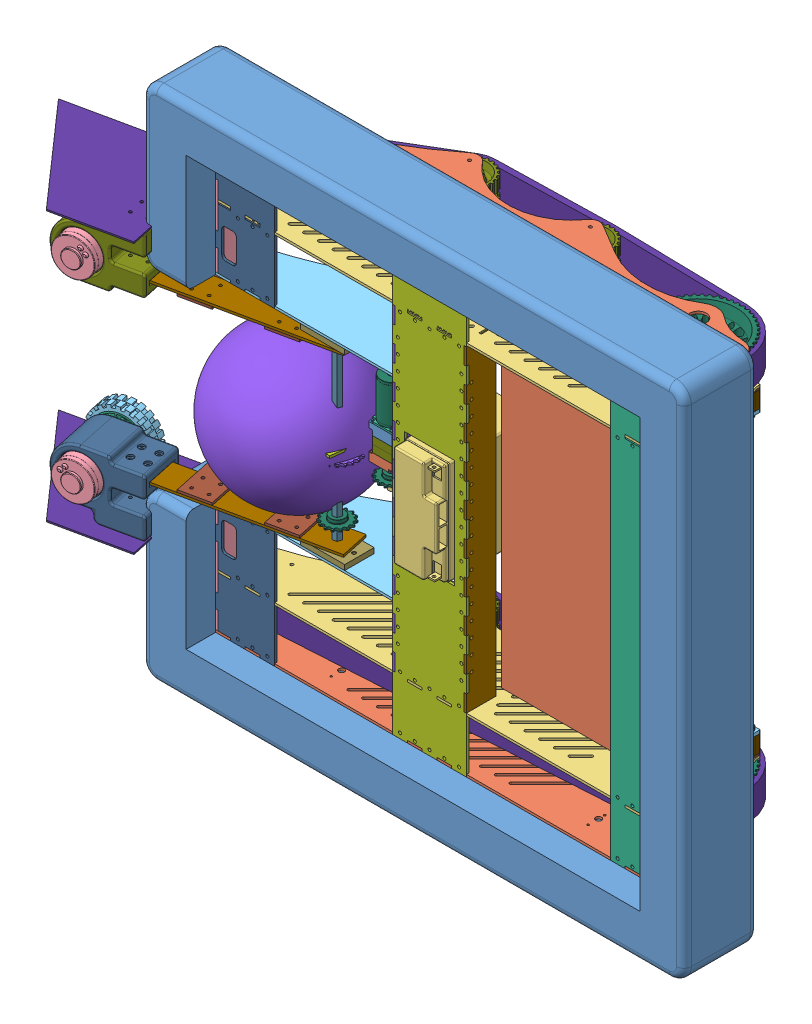
SolidWorks assembly 2016 Robot V2, configuration Default. Lengths in mm.
Overall size (1186.64 889 425.4).
244 component instances, 88 part files, 49 mates.
Components (placement in the parent):
- Rear-1: Rear [Default] at origin size (4.06 736.6 127)
- Side-1: Side [Default] at (-97.9 364.236 -84.1375) x (0 -1 0) z (0 0 1) size (4.06 781.05 206.38)
- Side-2: Side [Default] at (-97.9 -368.3 -84.1375) x (0 -1 0) z (0 0 1) size (4.06 781.05 206.38)
- Imported3-1: Imported3 [Default] at (-97.9 275.2905 -84.1375) x (0 -1 0) z (0 0 1) size (4.07 781.05 206.38)
- Imported3-2: Imported3 [Default] at (-97.9 -277.114 -84.1375) x (0 -1 0) z (0 0 1) size (4.07 781.05 206.38)
- Front-1: Front [Default] at (-781.05 266.7 25.4) size (4.06 203.2 76.2)
- Front-2: Front [Default] at (-776.986 -266.7 25.4) x (-1 0 0) z (0 0 1) size (4.06 203.2 76.2)
- Inside-1: Inside [Default] at (-97.9 165.1 -84.1375) x (0 -1 0) z (0 0 1) size (4.06 308.86 152.4)
- Inside-2: Inside [Default] at (-97.9 -169.164 -84.1375) x (0 -1 0) z (0 0 1) size (4.06 308.86 152.4)
- RearTop-1: RearTop [Default] at (-50.8 0 59.436) x (0 0 -1) z (1 0 0) size (4.06 736.6 101.6)
- Center-1: Center [Default] at (-412.75 0 63.5) x (0 0 1) z (-1 0 0) size (4.06 736.6 127)
- Imported8-1: Imported8 [Default] at (-476.25 0 25.4) size (4.06 554.23 76.2)
- Imported9-1: Imported9 [Default] at (-353.314 0 25.4) size (4.06 554.23 50.8)
- FrontTop-1: FrontTop [Default] at (-730.25 266.7 59.436) x (0 0 1) z (-1 0 0) size (4.06 203.2 101.6)
- FrontTop-2: FrontTop [Default] at (-730.25 -266.7 63.5) x (0 0 -1) z (-1 0 0) size (4.06 203.2 101.6)
- Imported11-1: Imported11 [Default] at (-63.0846 163.0378 -87.64) x (-1 0 0.000624) z (0 1 0) size (146.08 127 198.84)
  - Imported11-1: Imported11 [Default] at (-3.3906 30.1762 78.8009) size (17.53 17.53 1.47)
  - Imported12-1: Imported12 [Default] at (73.0258 30.1762 94.4473) x (0 0 1) z (-1 0 0) size (1.12 14.83 14.83)
  - Imported13-1: Imported13 [Default] at (33.4941 11.4893 125.5831) x (0 0 1) z (-0.997664 0.068316 0) size (17.78 3.17 3.18)
  - Imported14-1: Imported14 [Default] at (-20.7449 79.3887 68.1837) x (1 0 0) z (0 1 0) size (9.53 57.35 9.53)
  - Imported15-1: Imported15 [Default] at (40.6889 53.1471 81.8489) x (0.923728 0.383049 0) z (0 0 -1) size (24.69 24.69 7.16)
  - Imported15-2: Imported15 [Default] at (43.7045 38.1296 107.5537) size (24.69 24.69 7.16)
  - Imported16-1: Imported16 [Default] at (90.4055 79.3887 112.2527) x (1 0 0) z (0 -1 0) size (11.11 8.13 12.83)
  - Imported11-2: Imported11 [Default] at (-3.3906 30.1762 80.2741) size (17.53 17.53 1.47)
  - Imported17-1: Imported17 [Default] at (62.138 11.0174 96.4031) x (1 0 0) z (0 1 0) size (19.07 1.27 20.95)
  - Imported18-1: Imported18 [Default] at (-20.7449 79.3887 80.3249) size (127 14.35 28.75)
  - Imported14-2: Imported14 [Default] at (-20.7449 -31.7363 68.1837) x (1 0 0) z (0 1 0) size (9.53 57.35 9.53)
  - Imported19-1: Imported19 [Default] at (-3.3906 4.7762 85.1509) x (0 0 -1) z (1 0 0) size (17.53 7.94 7.94)
  - Imported20-1: Imported20 [Default] at (43.7045 -2.5612 107.5029) size (31.75 31.75 7.95)
  - Imported21-1: Imported21 [Default] at (34.8176 3.4808 154.3659) x (0 0 -1) z (1 0 0) size (1.4 15.88 15.88)
  - Imported11-3: Imported11 [Default] at (73.0258 30.1762 78.8009) size (17.53 17.53 1.47)
  - Imported22-1: Imported22 [Default] at (34.8176 44.1716 92.0089) x (0 0 -1) z (1 0 0) size (10.16 65.97 66.04)
  - Imported23-1: Imported23 [Default] at (21.1445 38.6364 74.7369) x (1 0 0) z (0 1 0) size (127 5.59 127)
  - Imported14-3: Imported14 [Default] at (90.3801 -31.7363 68.1837) x (1 0 0) z (0 1 0) size (9.53 57.35 9.53)
  - Imported19-2: Imported19 [Default] at (-3.3906 55.5762 85.1509) x (0 0 -1) z (1 0 0) size (17.53 7.94 7.94)
  - Imported24-1: Imported24 [Default] at (-3.3906 30.1762 81.7473) size (20.03 20.32 12.7)
  - Imported25-1: Imported25 [Default] at (34.8176 3.4808 159.8269) x (0.554675 -0.832067 0) z (-0.832067 -0.554675 0) size (11.69 16.79 11.69)
  - Imported11-4: Imported11 [Default] at (73.0258 30.1762 80.2741) size (17.53 17.53 1.47)
  - Imported26-1: Imported26 [Default] at (34.843 44.1716 92.0089) x (0 0 1) z (-1 0 0) size (15.14 19.97 20.32)
  - Imported18-2: Imported18 [Default] at (90.4055 -31.7363 80.3249) x (-1 0 0) z (0 0 1) size (127 14.35 28.75)
  - Imported16-2: Imported16 [Default] at (-20.7195 79.3887 112.2527) x (1 0 0) z (0 -1 0) size (11.11 8.13 12.83)
  - Imported19-3: Imported19 [Default] at (73.0258 55.5762 85.1509) x (0 0 -1) z (1 0 0) size (17.53 7.94 7.94)
  - Imported24-2: Imported24 [Default] at (73.0258 30.1762 81.7473) x (0.98536 0.170489 0) z (0 0 1) size (20.03 20.32 12.7)
  - Imported27-1: Imported27 [Default] at (-25.2074 30.9762 84.4473) x (0 0 1) z (0 -1 0) size (10.51 2 2.25)
  - Imported28-1: Imported28 [Default] at (34.8176 3.4808 96.4031) x (0.997664 -0.068316 0) z (0 0 1) size (65.97 66.04 10.62)
  - Imported29-1: Imported29 [Default] at (21.1699 38.6364 109.0777) x (1 0 0) z (0 1 0) size (127 3.17 127)
  - Imported30-1: Imported30 [Default] at (34.8176 44.1716 75.8037) x (0.5 -0.866025 0) z (0 0 1) size (11 9.53 38.11)
  - Imported16-3: Imported16 [Default] at (-20.7195 -31.7363 112.2527) x (1 0 0) z (0 -1 0) size (11.11 8.13 12.83)
  - Imported19-4: Imported19 [Default] at (73.0258 4.7762 85.1509) x (0 0 -1) z (1 0 0) size (17.53 7.94 7.94)
  - Imported12-2: Imported12 [Default] at (-3.3906 30.1762 94.4473) x (0 0 1) z (-1 0 0) size (1.12 14.83 14.83)
  - Imported27-2: Imported27 [Default] at (79.0195 13.1317 84.4473) x (0 0 1) z (0.98536 0.170489 0) size (10.51 2 2.25)
  - Imported14-4: Imported14 [Default] at (90.3801 79.3887 68.1837) x (1 0 0) z (0 1 0) size (9.53 57.35 9.53)
  - Imported15-3: Imported15 [Default] at (40.6889 12.4563 81.8489) x (0.923728 0.383049 0) z (0 0 -1) size (24.69 24.69 7.16)
  - Imported31-1: Imported31 [Default] at (-2.2613 22.7278 107.2489) x (-0.997664 0.068316 0) z (0.068316 0.997664 0) size (14.66 92.33 12.7)
  - Imported16-4: Imported16 [Default] at (90.4055 -31.7363 112.2527) x (1 0 0) z (0 -1 0) size (11.11 8.13 12.83)
  - Imported32-1: Imported32 [Default] at (-3.3906 30.1762 67.7369) x (1 0 0) z (0 -1 0) size (69.66 149.34 65.98)
  - Imported32-2: Imported32 [Default] at (73.0258 30.1762 67.7369) x (1 0 0) z (0 -1 0) size (69.66 149.34 65.98)
- Imported11-2: Imported11 [Default] at (-132.7154 -160.7973 -87.64) x (1 0 0.000624) z (0 -1 0) size (146.08 127 198.84)
  - Imported11-1: Imported11 [Default] at (-3.3906 30.1762 78.8009) size (17.53 17.53 1.47)
  - Imported12-1: Imported12 [Default] at (73.0258 30.1762 94.4473) x (0 0 1) z (-1 0 0) size (1.12 14.83 14.83)
  - Imported13-1: Imported13 [Default] at (33.4941 11.4893 125.5831) x (0 0 1) z (-0.997664 0.068316 0) size (17.78 3.17 3.18)
  - Imported14-1: Imported14 [Default] at (-20.7449 79.3887 68.1837) x (1 0 0) z (0 1 0) size (9.53 57.35 9.53)
  - Imported15-1: Imported15 [Default] at (40.6889 53.1471 81.8489) x (0.923728 0.383049 0) z (0 0 -1) size (24.69 24.69 7.16)
  - Imported15-2: Imported15 [Default] at (43.7045 38.1296 107.5537) size (24.69 24.69 7.16)
  - Imported16-1: Imported16 [Default] at (90.4055 79.3887 112.2527) x (1 0 0) z (0 -1 0) size (11.11 8.13 12.83)
  - Imported11-2: Imported11 [Default] at (-3.3906 30.1762 80.2741) size (17.53 17.53 1.47)
  - Imported17-1: Imported17 [Default] at (62.138 11.0174 96.4031) x (1 0 0) z (0 1 0) size (19.07 1.27 20.95)
  - Imported18-1: Imported18 [Default] at (-20.7449 79.3887 80.3249) size (127 14.35 28.75)
  - Imported14-2: Imported14 [Default] at (-20.7449 -31.7363 68.1837) x (1 0 0) z (0 1 0) size (9.53 57.35 9.53)
  - Imported19-1: Imported19 [Default] at (-3.3906 4.7762 85.1509) x (0 0 -1) z (1 0 0) size (17.53 7.94 7.94)
  - Imported20-1: Imported20 [Default] at (43.7045 -2.5612 107.5029) size (31.75 31.75 7.95)
  - Imported21-1: Imported21 [Default] at (34.8176 3.4808 154.3659) x (0 0 -1) z (1 0 0) size (1.4 15.88 15.88)
  - Imported11-3: Imported11 [Default] at (73.0258 30.1762 78.8009) size (17.53 17.53 1.47)
  - Imported22-1: Imported22 [Default] at (34.8176 44.1716 92.0089) x (0 0 -1) z (1 0 0) size (10.16 65.97 66.04)
  - Imported23-1: Imported23 [Default] at (21.1445 38.6364 74.7369) x (1 0 0) z (0 1 0) size (127 5.59 127)
  - Imported14-3: Imported14 [Default] at (90.3801 -31.7363 68.1837) x (1 0 0) z (0 1 0) size (9.53 57.35 9.53)
  - Imported19-2: Imported19 [Default] at (-3.3906 55.5762 85.1509) x (0 0 -1) z (1 0 0) size (17.53 7.94 7.94)
  - Imported24-1: Imported24 [Default] at (-3.3906 30.1762 81.7473) size (20.03 20.32 12.7)
  - Imported25-1: Imported25 [Default] at (34.8176 3.4808 159.8269) x (0.554675 -0.832067 0) z (-0.832067 -0.554675 0) size (11.69 16.79 11.69)
  - Imported11-4: Imported11 [Default] at (73.0258 30.1762 80.2741) size (17.53 17.53 1.47)
  - Imported26-1: Imported26 [Default] at (34.843 44.1716 92.0089) x (0 0 1) z (-1 0 0) size (15.14 19.97 20.32)
  - Imported18-2: Imported18 [Default] at (90.4055 -31.7363 80.3249) x (-1 0 0) z (0 0 1) size (127 14.35 28.75)
  - Imported16-2: Imported16 [Default] at (-20.7195 79.3887 112.2527) x (1 0 0) z (0 -1 0) size (11.11 8.13 12.83)
  - Imported19-3: Imported19 [Default] at (73.0258 55.5762 85.1509) x (0 0 -1) z (1 0 0) size (17.53 7.94 7.94)
  - Imported24-2: Imported24 [Default] at (73.0258 30.1762 81.7473) x (0.98536 0.170489 0) z (0 0 1) size (20.03 20.32 12.7)
  - Imported27-1: Imported27 [Default] at (-25.2074 30.9762 84.4473) x (0 0 1) z (0 -1 0) size (10.51 2 2.25)
  - Imported28-1: Imported28 [Default] at (34.8176 3.4808 96.4031) x (0.997664 -0.068316 0) z (0 0 1) size (65.97 66.04 10.62)
  - Imported29-1: Imported29 [Default] at (21.1699 38.6364 109.0777) x (1 0 0) z (0 1 0) size (127 3.17 127)
  - Imported30-1: Imported30 [Default] at (34.8176 44.1716 75.8037) x (0.5 -0.866025 0) z (0 0 1) size (11 9.53 38.11)
  - Imported16-3: Imported16 [Default] at (-20.7195 -31.7363 112.2527) x (1 0 0) z (0 -1 0) size (11.11 8.13 12.83)
  - Imported19-4: Imported19 [Default] at (73.0258 4.7762 85.1509) x (0 0 -1) z (1 0 0) size (17.53 7.94 7.94)
  - Imported12-2: Imported12 [Default] at (-3.3906 30.1762 94.4473) x (0 0 1) z (-1 0 0) size (1.12 14.83 14.83)
  - Imported27-2: Imported27 [Default] at (79.0195 13.1317 84.4473) x (0 0 1) z (0.98536 0.170489 0) size (10.51 2 2.25)
  - Imported14-4: Imported14 [Default] at (90.3801 79.3887 68.1837) x (1 0 0) z (0 1 0) size (9.53 57.35 9.53)
  - Imported15-3: Imported15 [Default] at (40.6889 12.4563 81.8489) x (0.923728 0.383049 0) z (0 0 -1) size (24.69 24.69 7.16)
  - Imported31-1: Imported31 [Default] at (-2.2613 22.7278 107.2489) x (-0.997664 0.068316 0) z (0.068316 0.997664 0) size (14.66 92.33 12.7)
  - Imported16-4: Imported16 [Default] at (90.4055 -31.7363 112.2527) x (1 0 0) z (0 -1 0) size (11.11 8.13 12.83)
  - Imported32-1: Imported32 [Default] at (-3.3906 30.1762 67.7369) x (1 0 0) z (0 -1 0) size (69.66 149.34 65.98)
  - Imported32-2: Imported32 [Default] at (73.0258 30.1762 67.7369) x (1 0 0) z (0 -1 0) size (69.66 149.34 65.98)
- Imported33-1: Imported33 [Default] at (-97.9 322.9073 -84.1375) x (1 0 0) z (0 -1 0) size (150.76 150.76 55)
- Imported33-2: Imported33 [Default] at (-97.9 -320.6832 -84.1375) x (1 0 0) z (0 -1 0) size (150.76 150.76 55)
- Imported34-1: Imported34 [Default] at (-326.5 322.9073 -127) x (1 0 0) z (0 -1 0) size (74.17 74.17 55)
- Imported34-2: Imported34 [Default] at (-529.7 322.9073 -122.2375) x (1 0 0) z (0 -1 0) size (74.17 74.17 55)
- Imported34-3: Imported34 [Default] at (-721.25 322.9073 -7.9375) x (1 0 0) z (0 -1 0) size (74.17 74.17 55)
- Imported34-4: Imported34 [Default] at (-326.5 -320.6832 -127) x (1 0 0) z (0 -1 0) size (74.17 74.17 55)
- Imported34-5: Imported34 [Default] at (-529.7 -320.6832 -122.2375) x (1 0 0) z (0 -1 0) size (74.17 74.17 55)
- Imported34-6: Imported34 [Default] at (-721.25 -320.6832 -7.9375) x (1 0 0) z (0 -1 0) size (74.17 74.17 55)
- Belt-1: Belt [Default] at (-97.9 -320.6832 -84.1375) x (0 -1 0) z (0 0 1) size (50 749.65 207.26)
- Belt-2: Belt [Default] at (-97.9 322.9073 -84.1375) x (0 -1 0) z (0 0 1) size (50 749.65 207.26)
- Imported36-1: Imported36 [Default] at (-46.609 -24.2798 -33.3802) x (0 0 -1) z (0 1 0) size (57.51 127.03 152.4)
- Bumpers-1: Bumpers [Default] at (58.7957 17.8751 -12.7) size (933.45 889 127.01)
- electrical pannel-1: electrical pannel [Default] at (-349.252 267.8202 -0.1479) x (0 -1 0) z (-1 0 0.000624) size (533.4 3.17 336.55)
- Robot Raido OM5P-AN-1: Robot Raido OM5P-AN [Default] at (-114.3 140.8202 2.8805) x (1 0 -0.000624) z (0 -1 0) size (69.89 25.47 95.8) (hidden)
- roboRIO-2: roboRIO [Default] at (-238.0682 170.8303 12.6097) x (1 0 -0.000624) z (0.000624 0 1) size (146.27 143.19 36.83) (hidden)
- Voltage Regulator Module-1: Voltage Regulator Module [Default] at (-282.4199 37.3519 10.0914) x (1 0 -0.000624) z (0 -1 0) size (56.39 27.88 51.56) (hidden)
- Power Distribution Panel-1: Power Distribution Panel [Default] at (-253.7472 -120.4748 9.6477) x (0 1 0) z (1 0 -0.000624) size (192.68 39.24 124.89) (hidden)
- Main Circuit Breaker 120A-1: Main Circuit Breaker 120A [Default] at (-53.594 -115.697 68.58) size (50.95 73.41 44.2) (hidden)
- Battery 12V-1: Battery 12V [Default] at (-388.6368 55.7869 -78.232) x (0 -1 0) z (0 0 1) size (177.8 76.2 167.13)
- Pneumatic Control Module-1: Pneumatic Control Module [Default] at (-200.9586 39.4117 7.3795) x (0 1 0) z (1 0 -0.000624) size (69.09 27.65 56.9) (hidden)
- talon-1: talon [Default] at (-88.9291 -231.3973 8.8344) x (0 1 0) z (1 0 -0.000624) size (30.21 20.94 104.68) (hidden)
- talon-2: talon [Default] at (-88.9291 -188.4847 8.8344) x (0 1 0) z (1 0 -0.000624) size (30.21 20.94 104.68) (hidden)
- talon-3: talon [Default] at (-88.9291 -102.6596 8.8344) x (0 1 0) z (1 0 -0.000624) size (30.21 20.94 104.68) (hidden)
- talon-4: talon [Default] at (-88.9291 -59.747 8.8344) x (0 1 0) z (1 0 -0.000624) size (30.21 20.94 104.68) (hidden)
- talon-5: talon [Default] at (-88.9291 -16.8344 8.8344) x (0 1 0) z (1 0 -0.000624) size (30.21 20.94 104.68) (hidden)
- talon-6: talon [Default] at (-88.9291 -145.5722 8.8344) x (0 1 0) z (1 0 -0.000624) size (30.21 20.94 104.68) (hidden)
- shooter v2-1: shooter v2 [Default] at (-476.25 165.1 -139.7) x (0 -1 0) z (-1 0 0) size (466.79 425.4 635.26) (flexible)
  - shooter boundry-1: shooter boundry [Default] at origin size (330.2 228.6 381) (hidden)
  - MiniCIM Motor-1: MiniCIM Motor [Default] at (-2.032 219.5677 468.844) x (0 0.978022 -0.208504) z (0 0.208504 0.978022) size (133.06 64.01 64.01)
  - 4 in HiGrip Wheel-1: 4 in HiGrip Wheel [Default] at (1.2293 197.6904 475.009) x (0 0.978022 -0.208504) z (-0.935788 0.073511 0.344815) size (35.12 101.6 101.6)
    - 4 in tread-1: 4 in tread [Default] at (-8.0517 2.5236 2.5343) size (25.4 101.6 101.6)
    - 4in 2013 Hub-1: 4in 2013 Hub [Default] at (-8.0517 2.5236 2.5343) size (35.12 82.55 82.55)
  - am-0320a_8mm_Key_Hub-1: am-0320a_8mm_Key_Hub [Default] at (-2.032 211.9293 470.4724) x (0.162565 -0.20573 -0.965012) z (0 -0.978022 0.208504) size (57.15 57.15 25.4)
  - am-0320a_8mm_Key_Hub-2: am-0320a_8mm_Key_Hub [Default] at (332.232 211.9293 470.4724) x (-0.795747 0.126276 0.592318) z (0 -0.978022 0.208504) size (57.15 57.15 25.4)
  - 4 in HiGrip Wheel-2: 4 in HiGrip Wheel [Default] at (330.8694 196.6949 470.3393) x (0 0.978022 -0.208504) z (0.922364 0.08055 0.377832) size (35.12 101.6 101.6)
    - 4 in tread-1: 4 in tread [Default] at (-8.0517 2.5236 2.5343) size (25.4 101.6 101.6)
    - 4in 2013 Hub-1: 4in 2013 Hub [Default] at (-8.0517 2.5236 2.5343) size (35.12 82.55 82.55)
  - MiniCIM Motor-2: MiniCIM Motor [Default] at (332.232 219.5677 468.844) x (0 0.978022 -0.208504) z (1 0 0) size (133.06 64.01 64.01)
  - ball-1: ball [Default] at (185.504 150.271 215.6704) x (0.724331 -0.676335 -0.133854) z (-0.671375 -0.64775 -0.360105) size (254 254 254)
  - shooter bar-1: shooter bar [Default] at (317.5 147.6623 101.1042) x (0 0.208504 0.978022) z (-1 0 0) size (330.2 50.8 4.06)
  - shooter bar-2: shooter bar [Default] at (16.764 147.6623 101.1042) x (0 0.208504 0.978022) z (-1 0 0) size (330.2 50.8 4.06)
  - CIM mount - right - 3d print-2: CIM mount - right - 3d print [Default] at (287.782 222.6252 513.6411) x (1 0 0) z (0 0.208504 0.978022) size (107.95 76.2 139.7)
  - shooter cross bar-3: shooter cross bar [Default] at (16.764 11.8517 194.9846) x (1 0 0) z (0 0.208504 0.978022) size (296.67 203.2 50.8)
  - shooter cross bar-4: shooter cross bar [Default] at (16.764 38.3317 319.1933) x (1 0 0) z (0 0.208504 0.978022) size (296.67 203.2 50.8)
  - bearing block-1: bearing block [Default] at (330.2 203.2 82.55) x (0 -1 0) z (-1 0 0) size (50.8 76.2 8.89)
  - bearing block-2: bearing block [Default] at (0 152.4 82.55) x (0 1 0) z (1 0 0) size (50.8 76.2 8.89)
  - .5in hex bearing-3: .5in hex bearing [Default] at (327.66 177.8 120.65) x (0 0.951243 0.308441) z (0 -0.308441 0.951243) size (31.72 7.92 31.72)
  - .5in hex bearing-4: .5in hex bearing [Default] at (2.54 177.8 120.65) x (0 -0.951243 -0.308441) z (0 -0.308441 0.951243) size (31.72 7.92 31.72)
  - shaft-2: shaft [Default] at (330.2 177.8 120.65) x (0 0.74274 -0.66958) z (-1 0 0) size (14.66 12.7 330.2)
  - s35-15he-500h-1: s35-15he-500h [Default] at (283.972 177.8 120.65) x (0 -0.208504 -0.978022) z (-1 0 0) size (50.14 50.4 10.29)
  - CIM mount - left - 3d print-1: CIM mount - left - 3d print [Default] at (42.418 222.6252 513.6411) x (1 0 0) z (0 0.208504 0.978022) size (107.95 76.2 139.7)
  - gate lifter-1: gate lifter [Default] at (395.732 144.4422 634.1921) x (0 -0.208504 -0.978022) z (1 0 0) size (241.3 203.2 2.54)
  - gate lifter-2: gate lifter [Default] at (-68.072 144.4422 634.1921) x (0 -0.208504 -0.978022) z (1 0 0) size (241.3 203.2 2.54)
  - bottom bar-1: bottom bar [Default] at (190.5 44.949 369.7242) x (0 -0.208504 -0.978022) z (1 0 0) size (177.8 4.06 50.8)
  - VEXpro-VersaPlanetary-2stage-with-BAG-1: VEXpro-VersaPlanetary-2stage-with-BAG [Default] at (215.175 106 33.7) x (0 0 1) z (-1 0 0) size (49.3 49.3 173.58)
    - 217-2625-001 Rev1-1: 217-2625-001 Rev1 [Default] at origin size (42 42 18)
    - 217-2625-002 Rev1-1: 217-2625-002 Rev1 [Default] at (0 0 -29.4) size (42 42 17.13)
    - 217-2625-003 Rev1-1: 217-2625-003 Rev1 [Default] at (0 0 -43.6478) x (0.966651 -0.256095 0) z (0 0 -1) size (17 17 64.12)
    - 217-2625-009 Rev1-1: 217-2625-009 Rev1 [Default] at (0 0 -3.48) x (-0.609619 0.792694 0) z (0 0 -1) size (18 18 13)
    - 217-2625-100-1: 217-2625-100 [Default] at (0 0 -18.8454) x (0.784104 -0.62063 0) z (0 0 1) size (39.26 38.9 12.7)
      - 217-2625-008 Rev1-1: 217-2625-008 Rev1 [Default] at origin size (34.7 34.7 4.7)
      - 217-2625-010 Rev1-1: 217-2625-010 Rev1 [Default] at (0 10.193 3.65) x (0.999813 0.019336 0) z (0 0 1) size (4 4 12)
      - 217-2625-010 Rev1-2: 217-2625-010 Rev1 [Default] at (8.691 -5.3258 3.65) size (4 4 12)
      - 217-2625-010 Rev1-3: 217-2625-010 Rev1 [Default] at (-8.691 -5.3258 3.65) size (4 4 12)
      - 217-2625-005 Rev1_Planet_Revolving_Follower01-1: 217-2625-005 Rev1_Planet_Revolving_Follower01 [Default] at (8.691 -5.3258 6.35) x (0.932816 0.360354 0) z (0 0 1) size (16.91 16.92 8)
      - 217-2625-005 Rev1_Planet_Revolving_Follower01-2: 217-2625-005 Rev1_Planet_Revolving_Follower01 [Default] at (-8.691 -5.3258 6.35) x (-0.932788 -0.360426 0) z (0 0 1) size (16.91 16.92 8)
      - 217-2625-005 Rev1_Planet_Revolving_Follower01-3: 217-2625-005 Rev1_Planet_Revolving_Follower01 [Default] at (0 10.193 6.35) x (0.893583 0.448898 0) z (0 0 1) size (16.91 16.92 8)
    - 217-2625-007 Rev1_Sun_Driver01-1: 217-2625-007 Rev1_Sun_Driver01 [Default] at (0 0 -11.5575) x (0.564419 -0.825488 0) z (0 0 1) size (14.49 14.49 12.72)
    - 217-2742-1: 217-2742 [Default] at (0 0 -51.4002) x (0 0 1) z (-0.997393 0.072165 0) size (7 28 28)
    - 217-2742-2: 217-2742 [Default] at (0 0 -43.1002) x (0 0 1) z (-1 0 0) size (7 28 28)
    - 217-2741-1: 217-2741 [Default] at (0 0 -7) x (0 0 1) z (-0.951311 0.308231 0) size (5 26 26)
    - TRUARC-MSH-15_98541A410-1: TRUARC-MSH-15_98541A410 [Default] at (0 0 -35.4954) x (0 0 -1) z (0.980859 -0.194721 0) size (1 19.6 17.4)
    - SPRGW0856-1102-012_9714K62-1: SPRGW0856-1102-012_9714K62 [Default] at (0 0 -44.1002) x (-0.695225 0.718792 0) z (-0.718792 -0.695225 0) size (29.09 5.11 30.79)
    - SSS1032-0125ZB_94105A824-1: SSS1032-0125ZB_94105A824 [Default] at (5.4759 4.2112 1.995) x (-0.605001 0.78669 -0.122849) z (0.792694 0.609619 0) size (4.83 4.84 3.3)
    - TRUARC-5103-68_97414A675_grv-1: TRUARC-5103-68_97414A675_grv [Default] at (1.1965 0.0349 -1.3834) x (0 0 -1) z (-0.029125 0.999576 0) size (1.07 15.49 20.19)
    - 217-3351-1: 217-3351 [Default] at (0 0 10.675) x (0 -1 0) z (0 0 -1) size (40.4 40.4 81.5)
    - 217-2816-001 Rev1-1: 217-2816-001 Rev1 [Default] at (0 0 -29.55) x (1 0 0) z (0 0 -1) size (42 42 14.5)
    - SSA_SSA0832-1750ZC-1: SSA_SSA0832-1750ZC [Default] at (-17.5 17.5 -47.261) x (-0.769034 -0.639207 0) z (0.639207 -0.769034 0) size (6.73 48.51 6.73)
    - SSA_SSA0832-1750ZC-2: SSA_SSA0832-1750ZC [Default] at (17.5 -17.5 -47.261) x (0.162252 0.986749 0) z (-0.986749 0.162252 0) size (6.73 48.51 6.73)
    - 217-2625-011 Rev1-1: 217-2625-011 Rev1 [Default] at (0 0 1.37) x (-0.792694 -0.609619 0) z (-0.609619 0.792694 0) size (8.01 7.5 7.94)
    - SSA_SSA0832-0500ZC-1: SSA_SSA0832-0500ZC [Default] at (-17.5 17.5 10.675) x (0.592766 0.805375 0) z (0.805375 -0.592766 0) size (6.73 16.76 6.73)
    - SSA_SSA0832-0500ZC-2: SSA_SSA0832-0500ZC [Default] at (17.5 -17.5 10.675) x (-0.592766 -0.805375 0) z (-0.805375 0.592766 0) size (6.73 16.76 6.73)
    - SSHCM004_SSHCM004070010C-1: SSHCM004_SSHCM004070010C [Default] at (0 -12.5 7.5) x (-0.451598 -0.892221 0) z (0.892221 -0.451598 0) size (7 14 7)
    - SSHCM004_SSHCM004070010C-2: SSHCM004_SSHCM004070010C [Default] at (0 12.5 7.5) x (-0.447517 -0.894275 0) z (0.894275 -0.447517 0) size (7 14 7)
    - 217-2816-001 Rev1-2: 217-2816-001 Rev1 [Default] at (0 0 -16.85) x (1 0 0) z (0 0 -1) size (42 42 14.5)
    - 217-2818 Rev1-1: 217-2818 Rev1 [Default] at (0 0 -31.5454) size (49.07 49.07 17.4)
      - 217-2725-001 Rev1_24t Sun-1: 217-2725-001 Rev1_24t Sun [Default] at (0 0 8.7) size (14.45 14.45 12.7)
      - 217-2725-002 Rev1_24t Planet-1: 217-2725-002 Rev1_24t Planet [Default] at (-12.089 0 6.35) x (-0.130526 0.991445 0) z (0 0 -1) size (13.17 13.15 8)
      - 217-2724-002 Rev1-1: 217-2724-002 Rev1 [Default] x (0.707107 -0.707107 0) z (0 0 -1) size (34.7 34.7 4.7)
      - 217-2625-010 Rev1-1: 217-2625-010 Rev1 [Default] at (-12.089 0 3.65) x (0.971612 -0.236582 0) z (0 0 1) size (4 4 12)
      - 217-2725-002 Rev1_24t Planet-2: 217-2725-002 Rev1_24t Planet [Default] at (0 -12.089 6.35) x (-0.991445 -0.130526 0) z (0 0 -1) size (13.17 13.15 8)
      - 217-2725-002 Rev1_24t Planet-3: 217-2725-002 Rev1_24t Planet [Default] at (12.089 0 6.35) x (0.130526 -0.991445 0) z (0 0 -1) size (13.17 13.15 8)
      - 217-2725-002 Rev1_24t Planet-4: 217-2725-002 Rev1_24t Planet [Default] at (0 12.089 6.35) x (0.991445 0.130526 0) z (0 0 -1) size (13.17 13.15 8)
      - 217-2625-010 Rev1-2: 217-2625-010 Rev1 [Default] at (0 -12.089 3.65) x (0.236582 0.971612 0) z (0 0 1) size (4 4 12)
      - 217-2625-010 Rev1-3: 217-2625-010 Rev1 [Default] at (12.089 0 3.65) x (-0.971612 0.236582 0) z (0 0 1) size (4 4 12)
      - 217-2625-010 Rev1-4: 217-2625-010 Rev1 [Default] at (0 12.089 3.65) x (-0.236582 -0.971612 0) z (0 0 1) size (4 4 12)
    - 217-2822-003 Rev4-1: 217-2822-003 Rev4 [Default] at (0 0 9) x (0 -1 0) z (0 0 1) size (42 42 4.8)
  - s35-15he-500h-2: s35-15he-500h [Default] at (283.972 106 33.7) x (0 0.528305 -0.849055) z (-1 0 0) size (50.14 50.4 10.29)
  - .5in hex bearing-5: .5in hex bearing [Default] at (169.418 177.8 120.65) x (0 -0.208504 -0.978022) z (0 0.978022 -0.208504) size (31.72 7.92 31.72)
  - kicker-1: kicker [Default] at (163.068 29.7099 127.3655) x (0 0.126534 -0.991962) z (1 0 0) size (50.8 177.8 4.06)
  - VEXpro-VersaPlanetary-2stage-with-BAG-2: VEXpro-VersaPlanetary-2stage-with-BAG [Default] at (107.225 169.5 33.7) x (0 0 1) z (-1 0 0) size (49.3 49.3 173.58)
    - 217-2625-001 Rev1-1: 217-2625-001 Rev1 [Default] at origin size (42 42 18)
    - 217-2625-002 Rev1-1: 217-2625-002 Rev1 [Default] at (0 0 -29.4) size (42 42 17.13)
    - 217-2625-003 Rev1-1: 217-2625-003 Rev1 [Default] at (0 0 -43.6478) x (0.966651 -0.256095 0) z (0 0 -1) size (17 17 64.12)
    - 217-2625-009 Rev1-1: 217-2625-009 Rev1 [Default] at (0 0 -3.48) x (-0.609619 0.792694 0) z (0 0 -1) size (18 18 13)
    - 217-2625-100-1: 217-2625-100 [Default] at (0 0 -18.8454) x (0.784104 -0.62063 0) z (0 0 1) size (39.26 38.9 12.7)
      - 217-2625-008 Rev1-1: 217-2625-008 Rev1 [Default] at origin size (34.7 34.7 4.7)
      - 217-2625-010 Rev1-1: 217-2625-010 Rev1 [Default] at (0 10.193 3.65) x (0.999813 0.019336 0) z (0 0 1) size (4 4 12)
      - 217-2625-010 Rev1-2: 217-2625-010 Rev1 [Default] at (8.691 -5.3258 3.65) size (4 4 12)
      - 217-2625-010 Rev1-3: 217-2625-010 Rev1 [Default] at (-8.691 -5.3258 3.65) size (4 4 12)
      - 217-2625-005 Rev1_Planet_Revolving_Follower01-1: 217-2625-005 Rev1_Planet_Revolving_Follower01 [Default] at (8.691 -5.3258 6.35) x (0.932816 0.360354 0) z (0 0 1) size (16.91 16.92 8)
      - 217-2625-005 Rev1_Planet_Revolving_Follower01-2: 217-2625-005 Rev1_Planet_Revolving_Follower01 [Default] at (-8.691 -5.3258 6.35) x (-0.932788 -0.360426 0) z (0 0 1) size (16.91 16.92 8)
      - 217-2625-005 Rev1_Planet_Revolving_Follower01-3: 217-2625-005 Rev1_Planet_Revolving_Follower01 [Default] at (0 10.193 6.35) x (0.893583 0.448898 0) z (0 0 1) size (16.91 16.92 8)
    - 217-2625-007 Rev1_Sun_Driver01-1: 217-2625-007 Rev1_Sun_Driver01 [Default] at (0 0 -11.5575) x (0.564419 -0.825488 0) z (0 0 1) size (14.49 14.49 12.72)
    - 217-2742-1: 217-2742 [Default] at (0 0 -51.4002) x (0 0 1) z (-0.997393 0.072165 0) size (7 28 28)
    - 217-2742-2: 217-2742 [Default] at (0 0 -43.1002) x (0 0 1) z (-1 0 0) size (7 28 28)
    - 217-2741-1: 217-2741 [Default] at (0 0 -7) x (0 0 1) z (-0.951311 0.308231 0) size (5 26 26)
    - TRUARC-MSH-15_98541A410-1: TRUARC-MSH-15_98541A410 [Default] at (0 0 -35.4954) x (0 0 -1) z (0.980859 -0.194721 0) size (1 19.6 17.4)
    - SPRGW0856-1102-012_9714K62-1: SPRGW0856-1102-012_9714K62 [Default] at (0 0 -44.1002) x (-0.695225 0.718792 0) z (-0.718792 -0.695225 0) size (29.09 5.11 30.79)
    - SSS1032-0125ZB_94105A824-1: SSS1032-0125ZB_94105A824 [Default] at (5.4759 4.2112 1.995) x (-0.605001 0.78669 -0.122849) z (0.792694 0.609619 0) size (4.83 4.84 3.3)
    - TRUARC-5103-68_97414A675_grv-1: TRUARC-5103-68_97414A675_grv [Default] at (1.1965 0.0349 -1.3834) x (0 0 -1) z (-0.029125 0.999576 0) size (1.07 15.49 20.19)
    - 217-3351-1: 217-3351 [Default] at (0 0 10.675) x (0 -1 0) z (0 0 -1) size (40.4 40.4 81.5)
    - 217-2816-001 Rev1-1: 217-2816-001 Rev1 [Default] at (0 0 -29.55) x (1 0 0) z (0 0 -1) size (42 42 14.5)
    - SSA_SSA0832-1750ZC-1: SSA_SSA0832-1750ZC [Default] at (-17.5 17.5 -47.261) x (-0.769034 -0.639207 0) z (0.639207 -0.769034 0) size (6.73 48.51 6.73)
    - SSA_SSA0832-1750ZC-2: SSA_SSA0832-1750ZC [Default] at (17.5 -17.5 -47.261) x (0.162252 0.986749 0) z (-0.986749 0.162252 0) size (6.73 48.51 6.73)
    - 217-2625-011 Rev1-1: 217-2625-011 Rev1 [Default] at (0 0 1.37) x (-0.792694 -0.609619 0) z (-0.609619 0.792694 0) size (8.01 7.5 7.94)
    - SSA_SSA0832-0500ZC-1: SSA_SSA0832-0500ZC [Default] at (-17.5 17.5 10.675) x (0.592766 0.805375 0) z (0.805375 -0.592766 0) size (6.73 16.76 6.73)
    - SSA_SSA0832-0500ZC-2: SSA_SSA0832-0500ZC [Default] at (17.5 -17.5 10.675) x (-0.592766 -0.805375 0) z (-0.805375 0.592766 0) size (6.73 16.76 6.73)
    - SSHCM004_SSHCM004070010C-1: SSHCM004_SSHCM004070010C [Default] at (0 -12.5 7.5) x (-0.451598 -0.892221 0) z (0.892221 -0.451598 0) size (7 14 7)
    - SSHCM004_SSHCM004070010C-2: SSHCM004_SSHCM004070010C [Default] at (0 12.5 7.5) x (-0.447517 -0.894275 0) z (0.894275 -0.447517 0) size (7 14 7)
    - 217-2816-001 Rev1-2: 217-2816-001 Rev1 [Default] at (0 0 -16.85) x (1 0 0) z (0 0 -1) size (42 42 14.5)
    - 217-2818 Rev1-1: 217-2818 Rev1 [Default] at (0 0 -31.5454) size (49.07 49.07 17.4)
      - 217-2725-001 Rev1_24t Sun-1: 217-2725-001 Rev1_24t Sun [Default] at (0 0 8.7) size (14.45 14.45 12.7)
      - 217-2725-002 Rev1_24t Planet-1: 217-2725-002 Rev1_24t Planet [Default] at (-12.089 0 6.35) x (-0.130526 0.991445 0) z (0 0 -1) size (13.17 13.15 8)
      - 217-2724-002 Rev1-1: 217-2724-002 Rev1 [Default] x (0.707107 -0.707107 0) z (0 0 -1) size (34.7 34.7 4.7)
      - 217-2625-010 Rev1-1: 217-2625-010 Rev1 [Default] at (-12.089 0 3.65) x (0.971612 -0.236582 0) z (0 0 1) size (4 4 12)
      - 217-2725-002 Rev1_24t Planet-2: 217-2725-002 Rev1_24t Planet [Default] at (0 -12.089 6.35) x (-0.991445 -0.130526 0) z (0 0 -1) size (13.17 13.15 8)
      - 217-2725-002 Rev1_24t Planet-3: 217-2725-002 Rev1_24t Planet [Default] at (12.089 0 6.35) x (0.130526 -0.991445 0) z (0 0 -1) size (13.17 13.15 8)
      - 217-2725-002 Rev1_24t Planet-4: 217-2725-002 Rev1_24t Planet [Default] at (0 12.089 6.35) x (0.991445 0.130526 0) z (0 0 -1) size (13.17 13.15 8)
      - 217-2625-010 Rev1-2: 217-2625-010 Rev1 [Default] at (0 -12.089 3.65) x (0.236582 0.971612 0) z (0 0 1) size (4 4 12)
      - 217-2625-010 Rev1-3: 217-2625-010 Rev1 [Default] at (12.089 0 3.65) x (-0.971612 0.236582 0) z (0 0 1) size (4 4 12)
      - 217-2625-010 Rev1-4: 217-2625-010 Rev1 [Default] at (0 12.089 3.65) x (-0.236582 -0.971612 0) z (0 0 1) size (4 4 12)
    - 217-2822-003 Rev4-1: 217-2822-003 Rev4 [Default] at (0 0 9) x (0 -1 0) z (0 0 1) size (42 42 4.8)
  - s35-15he-500h-3: s35-15he-500h [Default] at (179.832 169.5 33.7) x (0 0.321712 -0.946838) z (-1 0 0) size (50.14 50.4 10.29)
  - am-0737-1: am-0737 [Default] at (181.864 177.8 120.65) x (0 0.795797 0.605563) z (-1 0 0) size (71.96 71.42 4.06)
Mates (geometry in assembly coordinates):
- Coincident1: coincident aligned: plane of Rear-1 through (-4.064 0 0) normal (-1 0 0); circle of Imported36-1
- Width1: width aligned: plane of Imported3-2 through (-97.9 -273.05 -84.1375) normal (0 1 0); plane of Imported3-1 through (-97.9 275.2905 -84.1375) normal (0 -1 0); plane of Imported36-1 through (-46.609 63.9852 -33.3802) normal (0 1 0); plane of Imported36-1 through (-46.609 -61.7448 -33.3802) normal (0 -1 0)
- Coincident3: coincident anti-aligned: plane of Imported11-1/Imported18-1 through (-42.2852 243.3627 -0.3395) normal (0.000624 0 1); plane of electrical pannel-1 through (-349.252 267.8202 -0.1479) normal (-0.000624 0 -1)
- Coincident15: coincident aligned: plane of electrical pannel-1 through (-349.25 267.8202 3.0271) normal (0.000624 0 1); plane of roboRIO-2 through (-311.5862 98.8637 3.0036) normal (0.000624 0 1)
- Distance3: distance = 25.4 mm: plane of roboRIO-2 through (-169.9988 242.4202 5.1474) normal (0 -1 0); line of electrical pannel-1 through (-12.7001 267.8202 2.817) axis (-1 0 0.000624)
- Coincident18: coincident anti-aligned: plane of electrical pannel-1 through (-349.25 267.8202 3.0271) normal (0.000624 0 1); plane of Voltage Regulator Module-1 through (-259.08 56.8992 2.9708) normal (-0.000624 0 -1)
- Distance7: distance = 38.1 mm: line of roboRIO-2 through (-303.5285 99.2404 5.3898) axis (1 0 -0.000624); line of Voltage Regulator Module-1 through (-259.08 61.2172 2.9454) axis (-1 0 0.000624)
- Width3: width anti-aligned: plane of Imported3-2 through (-97.9 -273.05 -84.1375) normal (0 1 0); plane of Imported3-1 through (-97.9 275.2905 -84.1375) normal (0 -1 0); plane of electrical pannel-1 through (-349.25 -265.5798 3.0271) normal (0 -1 0); plane of electrical pannel-1 through (-349.25 267.8202 3.0271) normal (0 1 0)
- Coincident25: coincident anti-aligned: plane of electrical pannel-1 through (-349.25 267.8202 3.0271) normal (0.000624 0 1); plane of Power Distribution Panel-1 through (-196.3474 -28.4506 2.9317) normal (-0.000624 0 -1)
- Coincident32: coincident: plane of Imported9-1 through (-349.25 0 25.4) normal (1 0 0); line of electrical pannel-1 through (-349.25 267.8202 3.0271) axis (0 -1 0)
- Distance11: distance = 38.1 mm: line of Voltage Regulator Module-1 through (-311.15 56.8992 2.9779) axis (0 -1 0); plane of electrical pannel-1 through (-349.25 267.8202 3.0271) normal (-1 0 0.000624)
- Distance13: distance = 38.1 mm: line of roboRIO-2 through (-311.1485 234.8002 5.3945) axis (0 -1 0); plane of electrical pannel-1 through (-349.25 267.8202 3.0271) normal (-1 0 0.000624)
- Width5: width anti-aligned: plane of Center-1 through (-369.8875 0 63.5) normal (-1 0 0); plane of Center-1 through (-455.6125 0 63.5) normal (1 0 0); plane of Battery 12V-1 through (-374.65 88.9 -78.232) normal (1 0 0); plane of Battery 12V-1 through (-450.85 88.9 -78.232) normal (-1 0 0)
- Width6: width aligned: plane of Center-1 through (-412.75 -93.6625 63.5) normal (0 1 0); plane of Center-1 through (-412.75 93.6625 63.5) normal (0 -1 0); plane of Battery 12V-1 through (-374.65 88.9 67.818) normal (0 1 0); plane of Battery 12V-1 through (-374.65 -88.9 -78.232) normal (0 -1 0)
- Distance15: distance = 25.4 mm aligned: plane of Battery 12V-1 through (-449.3726 -87.4226 88.9) normal (0 0 1); plane of Center-1 through (-412.75 0 63.5) normal (0 0 1)
- Coincident40: coincident anti-aligned: plane of electrical pannel-1 through (-349.25 267.8202 3.0271) normal (0.000624 0 1); plane of Pneumatic Control Module-1 through (-225.2692 8.9825 2.9497) normal (-0.000624 0 -1)
- Coincident45: coincident anti-aligned: plane of electrical pannel-1 through (-349.25 267.8202 3.0271) normal (0.000624 0 1); plane of talon-1 through (-88.9328 -231.3973 2.8646) normal (-0.000624 0 -1)
- Coincident50: coincident anti-aligned: plane of electrical pannel-1 through (-349.25 267.8202 3.0271) normal (0.000624 0 1); plane of talon-2 through (-88.9328 -188.4847 2.8646) normal (-0.000624 0 -1)
- Coincident57: coincident anti-aligned: plane of electrical pannel-1 through (-349.25 267.8202 3.0271) normal (0.000624 0 1); plane of talon-3 through (-88.9328 -102.6596 2.8646) normal (-0.000624 0 -1)
- Coincident61: coincident anti-aligned: plane of electrical pannel-1 through (-349.25 267.8202 3.0271) normal (0.000624 0 1); plane of talon-4 through (-88.9328 -59.747 2.8646) normal (-0.000624 0 -1)
- Coincident65: coincident anti-aligned: plane of electrical pannel-1 through (-349.25 267.8202 3.0271) normal (0.000624 0 1); plane of talon-5 through (-88.9328 -16.8344 2.8646) normal (-0.000624 0 -1)
- Distance41: distance = 25.4 mm: line of Pneumatic Control Module-1 through (-229.3586 33.2141 2.9523) axis (0 1 0); plane of Voltage Regulator Module-1 through (-254.762 56.8992 2.9427) normal (0.999858 0 0.016828)
- Coincident82: coincident anti-aligned: plane of electrical pannel-1 through (-349.25 267.8202 3.0271) normal (0.000624 0 1); plane of talon-6 through (-88.9328 -145.5722 2.8646) normal (-0.000624 0 -1)
- Distance47: distance = 6.35 mm: point of Imported36-1; plane of electrical pannel-1 through (-349.252 267.8202 -0.1479) normal (-0.000624 0 -1)
- Distance55: distance = 19.05 mm: plane of talon-1 through (-57.183 -246.5304 2.6448) normal (0.000011 -0.999848 0.017452); line of electrical pannel-1 through (-349.25 -265.5798 3.0271) axis (1 0 -0.000624)
- Distance56: distance = 44.45 mm: plane of talon-1 through (-57.1782 -246.3973 10.2648) normal (0.999993 0 0.003739); line of electrical pannel-1 through (-12.7001 -265.5798 2.817) axis (0 1 0)
- Coincident105: coincident aligned: plane of talon-1 through (-57.1782 -246.3973 10.2648) normal (0.999906 0 -0.013714); plane of talon-2 through (-57.1782 -203.4847 10.2648) normal (0.999906 0 -0.013714)
- Coincident106: coincident aligned: plane of talon-2 through (-57.1782 -203.4847 10.2648) normal (0.999906 0 -0.013714); plane of talon-6 through (-57.1782 -160.5722 10.2648) normal (0.999906 0 -0.013714)
- Distance57: distance = 12.7 mm: line of talon-1 through (-58.7515 -216.291 4.1759) axis (-1 0 0.000624); line of talon-2 through (-119.1125 -203.591 4.2136) axis (1 0 -0.000624)
- Distance58: distance = 12.7 mm: line of talon-6 through (-119.1125 -160.6785 4.2136) axis (1 0 -0.000624); line of talon-2 through (-58.7515 -173.3785 4.1759) axis (-1 0 0.000624)
- Coincident110: coincident aligned: plane of talon-3 through (-57.1782 -117.6596 10.2648) normal (0.999906 0 -0.013714); plane of talon-1 through (-57.1782 -246.3973 10.2648) normal (0.999906 0 -0.013714)
- Distance59: distance = 12.7 mm: line of talon-6 through (-58.7515 -130.4659 4.1759) axis (-1 0 0.000624); line of talon-3 through (-119.1125 -117.7659 4.2136) axis (1 0 -0.000624)
- Coincident112: coincident aligned: plane of talon-1 through (-57.1782 -246.3973 10.2648) normal (0.999906 0 -0.013714); plane of talon-4 through (-57.1782 -74.747 10.2648) normal (0.999906 0 -0.013714)
- Distance60: distance = 12.7 mm: line of talon-3 through (-58.7515 -87.5533 4.1759) axis (-1 0 0.000624); line of talon-4 through (-119.1125 -74.8533 4.2136) axis (1 0 -0.000624)
- Coincident114: coincident aligned: plane of talon-4 through (-57.1782 -74.747 10.2648) normal (0.999906 0 -0.013714); plane of talon-5 through (-57.1782 -31.8344 10.2648) normal (0.999906 0 -0.013714)
- Distance61: distance = 12.7 mm: line of talon-5 through (-119.1125 -31.9407 4.2136) axis (1 0 -0.000624); line of talon-4 through (-58.7515 -44.6407 4.1759) axis (-1 0 0.000624)
- Parallel25: parallel aligned: line of electrical pannel-1 through (-349.25 267.8202 3.0271) axis (0 -1 0); line of Power Distribution Panel-1 through (-311.1507 -38.2341 3.2618) axis (0 -1 0)
- Distance81: distance = 38.1 mm: line of Power Distribution Panel-1 through (-311.1507 -38.2341 3.2618) axis (0 -1 0); line of electrical pannel-1 through (-349.25 267.8202 3.0271) axis (0 -1 0)
- Distance82: distance = 44.45 mm: line of Power Distribution Panel-1 through (-201.558 -221.1305 3.1934) axis (-1 0 0.000624); line of electrical pannel-1 through (-349.25 -265.5798 3.0271) axis (1 0 -0.000624)
- Distance83: distance = 25.4 mm: line of Pneumatic Control Module-1 through (-176.0694 73.9557 2.8936) axis (-1 0 0.000624); line of roboRIO-2 through (-303.5285 99.2404 5.3898) axis (1 0 -0.000624)
- Coincident123: coincident anti-aligned: plane of electrical pannel-1 through (-349.25 267.8202 3.0271) normal (0.000624 0 1); plane of Robot Raido OM5P-AN-1 through (-102.8062 224.5764 2.8733) normal (-0.000624 0 -1)
- Distance84: distance = 101.6 mm: plane of Robot Raido OM5P-AN-1 through (-114.2842 140.8202 28.2804) normal (-1 0 0.000624); line of electrical pannel-1 through (-12.7001 -265.5798 2.817) axis (0 1 0)
- Distance85: distance = 127 mm: plane of Robot Raido OM5P-AN-1 through (-114.2842 140.8202 28.2804) normal (0 -1 0); line of electrical pannel-1 through (-12.7001 267.8202 2.817) axis (-1 0 0.000624)
- Coincident127: coincident anti-aligned: plane of RearTop-1 through (-50.8 0 63.5) normal (0 0 1); plane of Main Circuit Breaker 120A-1 through (-29.464 -78.994 63.5) normal (0 0 -1)
- Distance87: distance = 25.4 mm anti-aligned: plane of Main Circuit Breaker 120A-1 through (-29.464 -78.994 68.58) normal (1 0 0); plane of Rear-1 through (-4.064 0 0) normal (-1 0 0)
- Distance88: distance = 25.4 mm aligned: plane of Main Circuit Breaker 120A-1 through (-29.464 -152.4 68.58) normal (0 -1 0); plane of RearTop-1 through (-50.8 -177.8 59.436) normal (0 -1 0)
- Coincident128: coincident anti-aligned: plane of shooter v2-1/shooter boundry-1 through (-476.25 165.1 -139.7) normal (1 0 0); plane of Imported8-1 through (-476.25 0 25.4) normal (-1 0 0)
- Distance89: distance = 25.4 mm aligned: plane of shooter v2-1/shooter boundry-1 through (-857.25 165.1 88.9) normal (0 0 1); plane of Center-1 through (-412.75 0 63.5) normal (0 0 1)
- Width8: width aligned: plane of Inside-1 through (-97.9 165.1 -84.1375) normal (0 -1 0); plane of Inside-2 through (-97.9 -165.1 -84.1375) normal (0 1 0); plane of shooter v2-1/shooter boundry-1 through (-857.25 -165.1 -139.7) normal (0 -1 0); plane of shooter v2-1/shooter boundry-1 through (-857.25 165.1 -139.7) normal (0 1 0)
